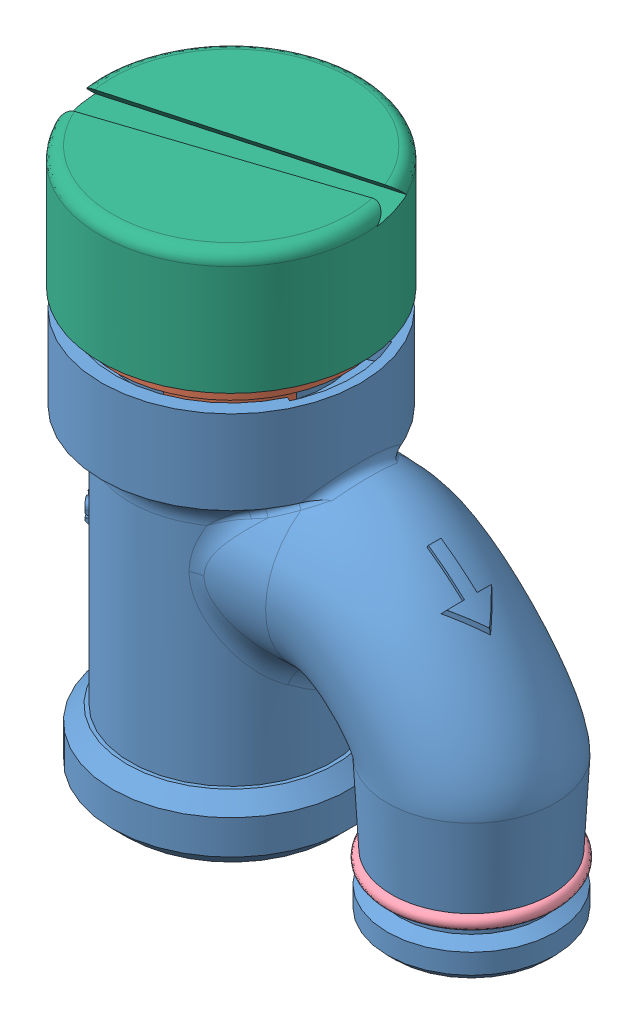
SolidWorks assembly tetra_concept-assembly-v5, configuration Default. Lengths in mm.
Overall size (64.94 71.85 44.52).
8 component instances, 7 part files, 16 mates.
Components (placement in the parent):
- tetra_concept-body-v5-1: tetra_concept-body-v5 [Default] at origin size (59.57 53.47 34.02)
- tetra_concept-top-v5-1: tetra_concept-top-v5 [Default] at (0 36.45 0) x (0.700064 0 0.71408) z (0.71408 0 -0.700064) size (30.8 17.93 32.18)
- tetra_concept-plunger_v5-1: tetra_concept-plunger_v5 [Default] at (0 9.4 0) x (0.110795 0 -0.993843) z (0.993843 0 0.110795) size (21 31.5 21)
- TETRA_oring-018-1: TETRA_oring-018 [Default] at (0 30.0167 0) x (0.201014 0 0.979588) z (0 1 0) size (22.33 22.33 1.78)
- TETRA_uncompressed-century_G-74CS-1: TETRA_uncompressed-century_G-74CS [Default] at (0 42.015 0) x (0.998885 0 0.047205) z (-0.047205 0 0.998885) size (5.31 4.86 5.35)
- tetra_concept-cap_v5-1: tetra_concept-cap_v5 [Default] at (0 53.4363 0) x (-0.289676 0 -0.957125) z (-0.957125 0 0.289676) size (34.3 16.68 34.3)
- TETRA_oring-020-2: TETRA_oring-020 [Default] at (0 -15.3896 0) x (0.999974 0 0.007197) z (0 1 0) size (25.5 25.5 1.78)
- TETRA_oring-018-2: TETRA_oring-018 [Default] at (31.505 -11.549 0) x (1 0 0) z (0 -1 0) size (22.33 22.33 1.78)
Mates (geometry in assembly coordinates):
- Concentric2: concentric: cylinder of tetra_concept-top-v5-1 through (0 32.6 0) axis (0 1 0) radius 15.4; cylinder of tetra_concept-body-v5-1 through (0 -3.5578 0) axis (0 -1 0) radius 17.01
- Angle4: planar angle = 0.034907 rad: line of tetra_concept-body-v5-1 through (13.0599 35 6.0899) axis (0.906308 0 0.422618); line of tetra_concept-top-v5-1 through (-14.0873 33.8 -1.8634) axis (0.994801 0 0.101834)
- Distance2: distance = 0.2 mm: plane of tetra_concept-body-v5-1 through (13.255 32.4 0) normal (0 1 0); plane of tetra_concept-top-v5-1 through (0 32.6 0) normal (0 -1 0)
- Concentric3: concentric: cylinder of tetra_concept-top-v5-1 through (0 35.198 0) axis (0 1 0) radius 3; cylinder of tetra_concept-plunger_v5-1 through (0 3.7228 0) axis (0 -1 0) radius 2.6
- Concentric4: concentric: cylinder of tetra_concept-top-v5-1 through (0 31.8203 0) axis (0 -1 0) radius 15.1; line of TETRA_oring-018-1 through (0 29.0388 0) axis (0 1 0)
- Lock1: lock: unknown of tetra_concept-top-v5-1; unknown of TETRA_oring-018-1
- Concentric5: concentric: cylinder of tetra_concept-plunger_v5-1 through (0 40.9 0) axis (0 -1 0) radius 1.7; line of TETRA_uncompressed-century_G-74CS-1 through (5.3445 0 44.6821) axis (0 0 -1)
- Coincident2: coincident: plane of tetra_concept-plunger_v5-1 through (0.2881 39.6 -2.584) normal (0 1 0); plane of TETRA_uncompressed-century_G-74CS-1 through (0 39.6 0) normal (0 1 0)
- Coincident3: coincident: plane of tetra_concept-plunger_v5-1 through (0 10.5 0) normal (0 -1 0); plane of ? through (0 10.5 0) normal (0 1 0)
- Concentric6: concentric: cylinder of tetra_concept-body-v5-1 through (0 -9.1414 0) axis (0 -1 0) radius 8; cone of tetra_concept-plunger_v5-1 through (0 12.4 0) axis (0 1 0)
- LimitDistance3: limit distance = 2.4 mm: plane of tetra_concept-body-v5-1 through (8 10 0) normal (0 1 0); plane of tetra_concept-plunger_v5-1 through (0 12.4 0) normal (0 -1 0)
- Concentric7: concentric: cylinder of tetra_concept-body-v5-1 through (0 -3.5578 0) axis (0 -1 0) radius 17.01; cylinder of tetra_concept-cap_v5-1 through (0 37.4363 0) axis (0 1 0) radius 17.15
- Concentric8: concentric: cylinder of tetra_concept-body-v5-1 through (0 -9.1414 0) axis (0 -1 0) radius 13.5657; line of TETRA_oring-020-2 through (1.9558 0 -16.3675) axis (0 0 1)
- Tangent3: tangent: plane of tetra_concept-body-v5-1 through (12.8373 -16.2786 0) normal (0 1 0); torus of TETRA_oring-020-2
- Concentric10: concentric: cylinder of tetra_concept-body-v5-1 through (31.505 4.6267 0) axis (0 1 0) radius 9.41; line of TETRA_oring-018-2 through (1.9558 31.505 -10.5711) axis (0 0 -1)
- Tangent5: tangent: plane of tetra_concept-body-v5-1 through (41.84 -10.66 0) normal (0 -1 0); torus of TETRA_oring-018-2
